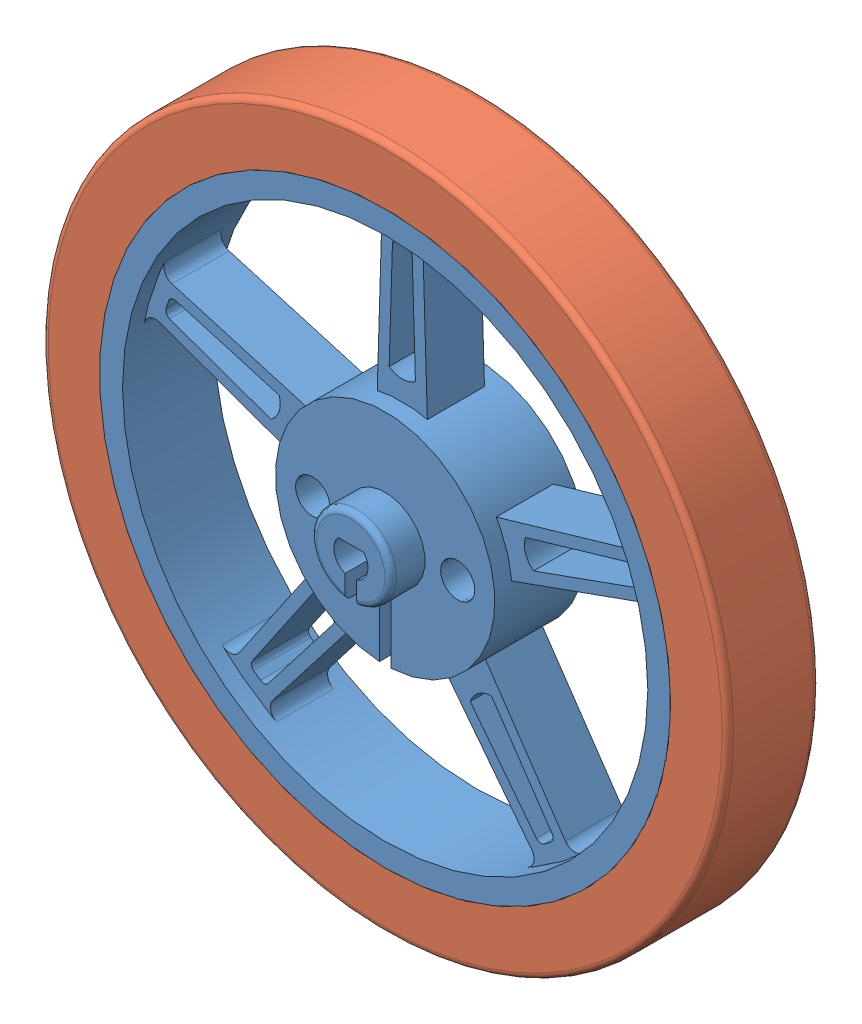
SolidWorks assembly PololuWheel 60x8mm, configuration Predeterminado. Lengths in mm.
Overall size (60 60 11.03).
2 component instances, 2 part files, 4 mates.
Components (placement in the parent):
- Part2^PololuWheel 60x8mm-1: Part2^PololuWheel 60x8mm [Default] x (0 0 -1) z (1 0 0) size (11.03 56 56) (virtual)
- Part3^PololuWheel 60x8mm-1: Part3^PololuWheel 60x8mm [Default] at origin size (60 60 8) (virtual)
Mates (geometry in assembly coordinates):
- InPlace1: in place: plane of Part2^PololuWheel 60x8mm-1 through (0 0 0) normal (1 0 0); moOrthogonalPlaneRef_w of Part2^PololuWheel 60x8mm-1 through (-55 0 0) axis (0 0 1); plane of Part2^PololuWheel 60x8mm-1 through (0 0 0) normal (0 0 -1); unknown of Part2^PololuWheel 60x8mm-1
- Coincident1: coincident aligned: plane of Part2^PololuWheel 60x8mm-1; plane of assembly
- Coincident2: coincident: plane of Part2^PololuWheel 60x8mm-1; moOrthogonalPlaneRef_w of assembly
- Coincident3: coincident anti-aligned: plane of Part2^PololuWheel 60x8mm-1 through (0 0 0) normal (0 0 -1); moOrthogonalPlaneRef_w of assembly
